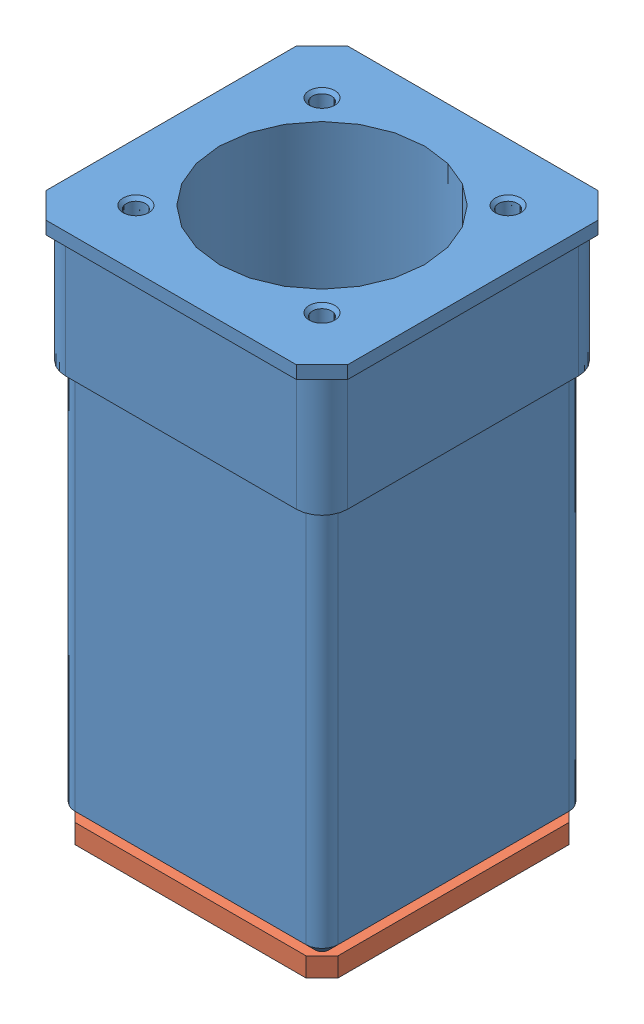
SolidWorks assembly Державка с нижней крышкой, configuration По умолчанию. Lengths in mm.
Overall size (47 86.66 47).
10 component instances, 4 part files, 19 mates.
Components (placement in the parent):
- Державка линейной направляющей-1: Державка линейной направляющей [По умолчанию] at origin size (47 80 47)
- Крышка державки лин напр-1: Крышка державки лин напр [По умолчанию] at (0 -3 0) x (1 0 0) z (0 1 0) size (41 41 3)
- Washer 6402_3_gost-1: Washer 6402_3_gost [Шайба 4 65Г 019 ГОСТ 6402-70] at (-14.4957 -3 14.4957) x (0.837169 0 0.546944) z (0.546944 0 -0.837169) size (6.1 1 6.1)
- Washer 6402_3_gost-2: Washer 6402_3_gost [Шайба 4 65Г 019 ГОСТ 6402-70] at (14.4957 -3 14.4957) x (0.837169 0 0.546944) z (0.546944 0 -0.837169) size (6.1 1 6.1)
- Washer 6402_3_gost-3: Washer 6402_3_gost [Шайба 4 65Г 019 ГОСТ 6402-70] at (14.4957 -3 -14.4957) x (0.837169 0 0.546944) z (0.546944 0 -0.837169) size (6.1 1 6.1)
- Washer 6402_3_gost-4: Washer 6402_3_gost [Шайба 4 65Г 019 ГОСТ 6402-70] at (-14.4957 -3 -14.4957) x (0.837169 0 0.546944) z (0.546944 0 -0.837169) size (6.1 1 6.1)
- SC GOST 17473_gost-1: SC GOST 17473_gost [Винт A.2.M4-6ex10.36.019 ГОСТ 17473-80] at (-14.4957 -6.8 14.4957) x (0 1 0) z (0 0 1) size (12.66 7.02 7.02)
- SC GOST 17473_gost-2: SC GOST 17473_gost [Винт A.2.M4-6ex10.36.019 ГОСТ 17473-80] at (14.4957 -6.8 14.4957) x (0 1 0) z (0 0 1) size (12.66 7.02 7.02)
- SC GOST 17473_gost-3: SC GOST 17473_gost [Винт A.2.M4-6ex10.36.019 ГОСТ 17473-80] at (14.4957 -6.8 -14.4957) x (0 1 0) z (0 0 1) size (12.66 7.02 7.02)
- SC GOST 17473_gost-4: SC GOST 17473_gost [Винт A.2.M4-6ex10.36.019 ГОСТ 17473-80] at (-14.4957 -6.8 -14.4957) x (0 1 0) z (0 0 1) size (12.66 7.02 7.02)
Mates (geometry in assembly coordinates):
- Совпадение1: coincident anti-aligned: plane of Державка линейной направляющей-1 through (20.5 0 -20.5) normal (0 -1 0); plane of Крышка державки лин напр-1 through (20.5 0 -20.5) normal (0 1 0)
- Концентрический1: concentric anti-aligned: cylinder of Державка линейной направляющей-1 through (0 0 0) axis (0 1 0) radius 16; cylinder of Крышка державки лин напр-1 through (0 0 0) axis (0 -1 0) radius 11
- Концентрический2: concentric anti-aligned: cylinder of Державка линейной направляющей-1 through (-14.4957 0 14.4957) axis (0 -1 0) radius 1.5; cylinder of Крышка державки лин напр-1 through (-14.4957 -3 14.4957) axis (0 1 0) radius 2.25
- Концентрический3: concentric anti-aligned: cylinder of Крышка державки лин напр-1 through (-14.4957 -3 14.4957) axis (0 1 0) radius 2.25; cylinder of Washer 6402_3_gost-1 through (-14.4957 -18.7597 14.4957) axis (0 -1 0) radius 2.05
- Совпадение2: coincident anti-aligned: plane of Крышка державки лин напр-1 through (20.5 -3 -20.5) normal (0 -1 0); plane of Washer 6402_3_gost-1 through (-16.2119 -3 13.3745) normal (0 1 0)
- Концентрический4: concentric anti-aligned: cylinder of Крышка державки лин напр-1 through (14.4957 -3 14.4957) axis (0 1 0) radius 2.25; cylinder of Washer 6402_3_gost-2 through (14.4957 -18.7597 14.4957) axis (0 -1 0) radius 2.05
- Совпадение3: coincident anti-aligned: plane of Крышка державки лин напр-1 through (20.5 -3 -20.5) normal (0 -1 0); plane of Washer 6402_3_gost-2 through (12.7795 -3 13.3745) normal (0 1 0)
- Концентрический5: concentric anti-aligned: cylinder of Крышка державки лин напр-1 through (14.4957 -3 -14.4957) axis (0 1 0) radius 2.25; cylinder of Washer 6402_3_gost-3 through (14.4957 -18.7597 -14.4957) axis (0 -1 0) radius 2.05
- Совпадение4: coincident anti-aligned: plane of Крышка державки лин напр-1 through (20.5 -3 -20.5) normal (0 -1 0); plane of Washer 6402_3_gost-3 through (12.7795 -3 -15.6169) normal (0 1 0)
- Концентрический6: concentric anti-aligned: cylinder of Крышка державки лин напр-1 through (-14.4957 -3 -14.4957) axis (0 1 0) radius 2.25; cylinder of Washer 6402_3_gost-4 through (-14.4957 -18.7597 -14.4957) axis (0 -1 0) radius 2.05
- Совпадение5: coincident anti-aligned: plane of Крышка державки лин напр-1 through (20.5 -3 -20.5) normal (0 -1 0); plane of Washer 6402_3_gost-4 through (-16.2119 -3 -15.6169) normal (0 1 0)
- Концентрический7: concentric anti-aligned: cylinder of Крышка державки лин напр-1 through (-14.4957 -3 14.4957) axis (0 1 0) radius 2.25; cylinder of SC GOST 17473_gost-1 through (-14.4957 -32.2 14.4957) axis (0 -1 0) radius 2
- Совпадение6: coincident anti-aligned: plane of Washer 6402_3_gost-1 through (-16.2119 -4 13.3745) normal (0 -1 0); plane of SC GOST 17473_gost-1 through (-16.4957 -4 14.4957) normal (0 1 0)
- Концентрический8: concentric aligned: cylinder of Washer 6402_3_gost-2 through (14.4957 -18.7597 14.4957) axis (0 -1 0) radius 3.05; cylinder of SC GOST 17473_gost-2 through (14.4957 -32.2 14.4957) axis (0 -1 0) radius 2
- Совпадение7: coincident anti-aligned: plane of Washer 6402_3_gost-2 through (12.7795 -4 13.3745) normal (0 -1 0); plane of SC GOST 17473_gost-2 through (12.4957 -4 14.4957) normal (0 1 0)
- Концентрический9: concentric aligned: cylinder of Washer 6402_3_gost-3 through (14.4957 -18.7597 -14.4957) axis (0 -1 0) radius 3.05; cylinder of SC GOST 17473_gost-3 through (14.4957 -32.2 -14.4957) axis (0 -1 0) radius 2
- Совпадение8: coincident anti-aligned: plane of Washer 6402_3_gost-3 through (12.7795 -4 -15.6169) normal (0 -1 0); plane of SC GOST 17473_gost-3 through (12.4957 -4 -14.4957) normal (0 1 0)
- Концентрический10: concentric anti-aligned: cylinder of Крышка державки лин напр-1 through (-14.4957 -3 -14.4957) axis (0 1 0) radius 2.25; cylinder of SC GOST 17473_gost-4 through (-14.4957 -32.2 -14.4957) axis (0 -1 0) radius 2
- Совпадение9: coincident anti-aligned: plane of Washer 6402_3_gost-4 through (-16.2119 -4 -15.6169) normal (0 -1 0); plane of SC GOST 17473_gost-4 through (-16.4957 -4 -14.4957) normal (0 1 0)
